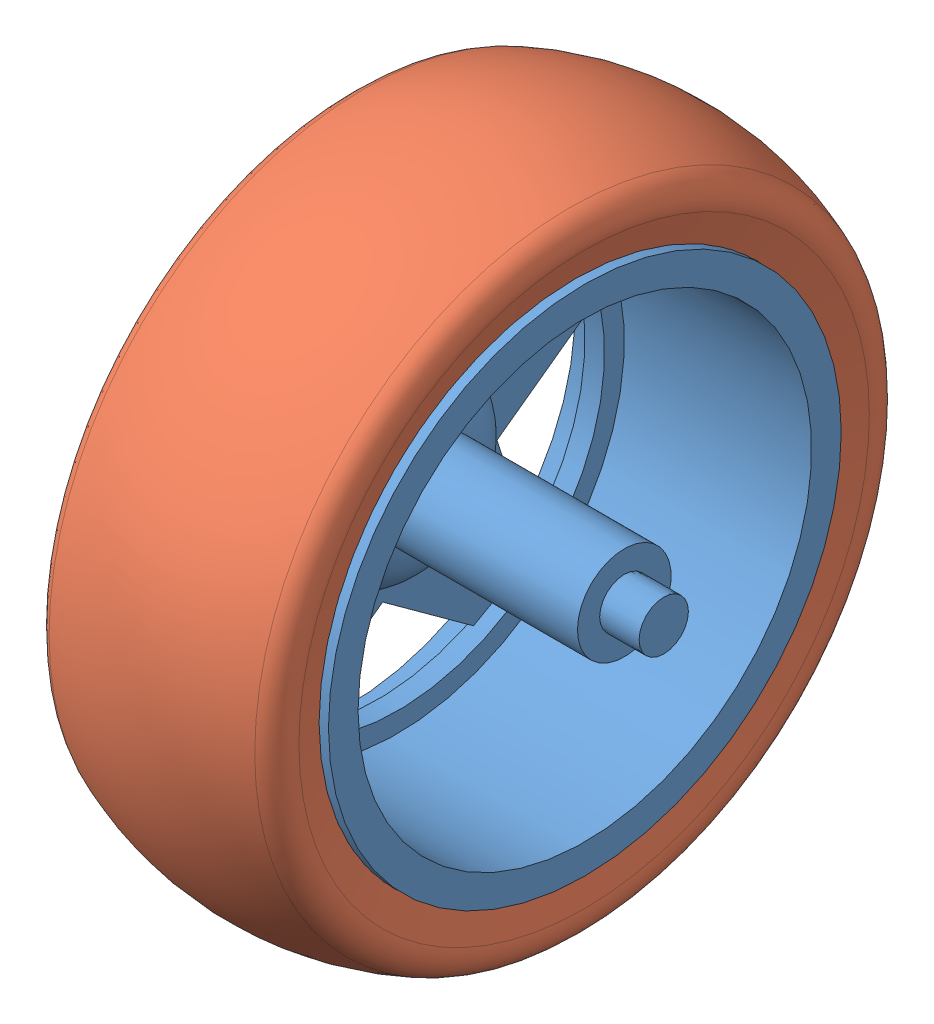
SolidWorks assembly Montagem1, configuration Valor predeterminado. Lengths in mm.
Overall size (32 68 68).
2 component instances, 2 part files, 3 mates.
Components (placement in the parent):
- aro-2: aro [Valor predeterminado] at origin size (32 52 52)
- pneu-2: pneu [Valor predeterminado] at (-0.45 0 0) size (23.96 68 68)
Mates (geometry in assembly coordinates):
- Coincidente1: coincident aligned: plane of aro-2 through (0 0 0) normal (0 0 1); plane of pneu-2 through (-0.5 0 0) normal (0 0 1)
- Coincidente2: coincident aligned: plane of aro-2 through (0 0 0) normal (0 1 0); plane of pneu-2 through (-0.5 0 0) normal (0 1 0)
- Distância1: distance = 0.45 mm aligned: plane of aro-2 through (0 0 0) normal (1 0 0); plane of pneu-2 through (-0.45 0 0) normal (1 0 0)
